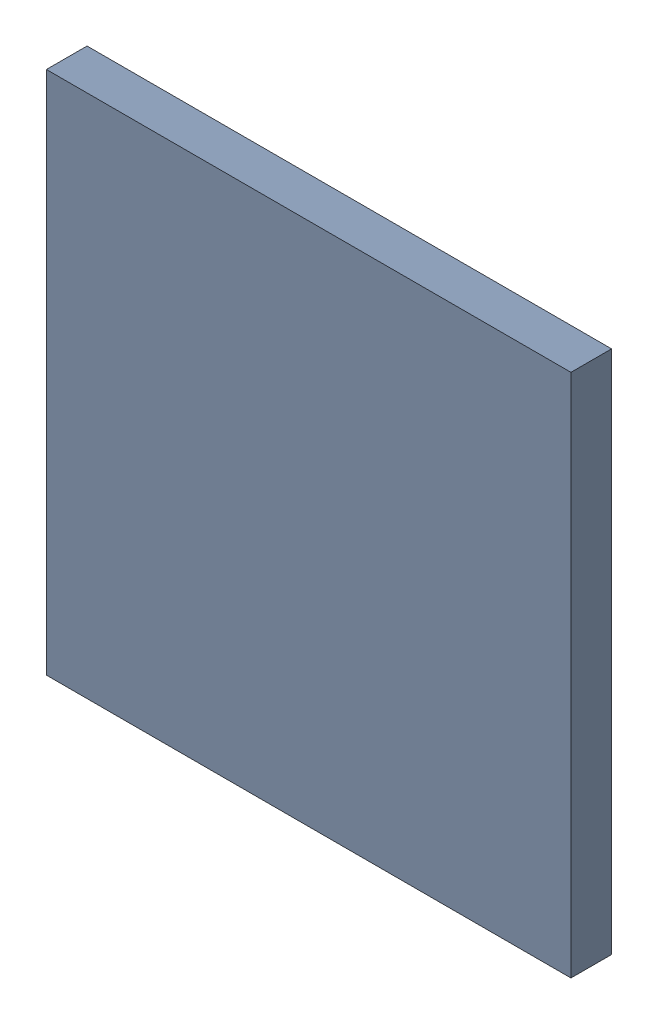
SolidWorks assembly XMC4500, configuration Standard. Lengths in mm.
Overall size (20 20 1.55).
2 component instances, 1 part files, 0 mates.
Components (placement in the parent):
- 885541424-1: 885541424 [Standard] at (-4.55 0 0.05) size (20 20 1.55)
  - Extruded_34-1: Extruded_34 [Standard] at origin size (20 20 1.55)
